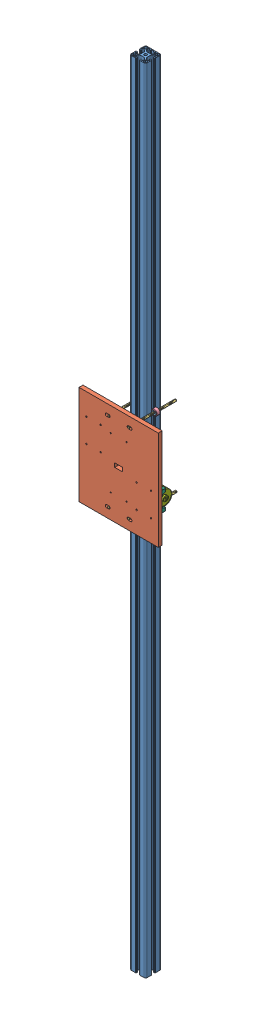
SolidWorks assembly assemblagecomplet, configuration Défaut. Lengths in mm.
Overall size (275.25 2000 121.11).
48 component instances, 14 part files, 17 mates.
Components (placement in the parent):
- rail-1: rail [Défaut] at (-24.0212 110.7646 2000) size (40 2000 40)
- suppport ameliore-1: suppport ameliore [Défaut] at (-123.9247 367.414 2058.0867) size (275.25 250 10)
- TigeFilet-1: TigeFilet [Défaut] at (-48.9247 342.414 2068.0867) x (1 0 0) z (0 1 0) size (5.15 120.44 5.77)
- TigeFilet-2: TigeFilet [Défaut] at (1.0753 342.414 2068.7589) x (-0.923728 -0.383049 0) z (0.383049 -0.923728 0) size (5.15 120.44 5.77)
- TigeFilet-3: TigeFilet [Défaut] at (1.0753 142.414 2068.0961) x (-0.923728 -0.383049 0) z (0.383049 -0.923728 0) size (5.15 120.44 5.77)
- TigeFilet-4: TigeFilet [Défaut] at (-48.9247 142.414 2068.4052) x (-0.728868 0.684654 0) z (-0.684654 -0.728868 0) size (5.15 120.44 5.77)
- RoueVAssemblage1-1: RoueVAssemblage1 [Défaut] at (-46.4189 341.2706 1984.8207) x (0.996447 0.084223 0) z (0 0 1) size (15.2 15.2 9)
  - RoueV1-1: RoueV1 [Défaut] at (-2.4006 1.3504 10.7) size (15.2 15.2 9)
  - RoueV2-1: RoueV2 [Défaut] at (-2.4006 1.3504 10.7) x (0.999854 -0.017094 0) z (0 0 1) size (10 10 9)
- SousAssemblageMoteurComplet-1: SousAssemblageMoteurComplet [Défaut] at (-133.3233 512.2521 1925.5591) x (1 0 0) z (0 -1 0) size (134.9 58.55 89.71)
  - MoteurEtSupport-1: MoteurEtSupport [Défaut] at (175.3767 115.3051 355.1381) x (0 1 0) z (0 0 -1) size (42.55 57.9 70)
    - SupportMoteur-1: SupportMoteur [Défaut] at (-2.7774 -21.4781 70) size (42.55 52 70)
    - Moteur-1: Moteur [Défaut] at (-4.7774 18.5219 45) x (1 0 0) z (0 -1 0) size (35.75 35.75 56.7)
  - piecemaintientchariot-1: piecemaintientchariot [Défaut] at (103.8575 100.6487 331.5754) size (50 31.79 18)
  - RoulementàBilles-1: RoulementàBilles [Défaut] at (106.8021 108.7409 335.5754) size (4 10 10)
  - Tige_entre_roues-1: Tige_entre_roues [Défaut] at (63.9986 108.7409 335.5754) size (80 3 3)
  - RoueAssemblee-1: RoueAssemblee [Défaut] at (119.9243 114.0834 363.6739) x (-1 0 0) z (0 -0.197919 -0.980218) size (16.9 28.6 28.6)
    - Roue1-1: Roue1 [Défaut] at (-7.3778 0.3244 28.6) size (13 28.6 28.6)
    - Roue2-1: Roue2 [Défaut] at (-7.6778 0.3244 28.6) x (0 -1 0) z (0 0 1) size (19 16.9 19)
  - RoueAssemblee-2: RoueAssemblee [Défaut] at (98.6799 108.2781 306.9773) x (1 0 0) z (0 0.004838 0.999988) size (16.9 28.6 28.6)
    - Roue1-1: Roue1 [Défaut] at (-7.3778 0.3244 28.6) size (13 28.6 28.6)
    - Roue2-1: Roue2 [Défaut] at (-7.6778 0.3244 28.6) x (0 -1 0) z (0 0 1) size (19 16.9 19)
  - PEngrenage-1: PEngrenage [Défaut] at (140.9986 110.5276 310.1381) x (1 0 0) z (0 0.064382 0.997925) size (7.5 9 9)
  - Gengrenage-1: Gengrenage [Défaut] at (143.9986 108.7409 335.5754) x (0 -0.815974 -0.578088) z (0 0.578088 -0.815974) size (42 8.4 42)
- SousAssemblageMoteurComplet-2: SousAssemblageMoteurComplet [Défaut] at (85.4739 -27.4241 1925.5591) x (-1 0 0) z (0 1 0) size (134.9 58.55 89.71)
  - MoteurEtSupport-1: MoteurEtSupport [Défaut] at (175.3767 115.3051 355.1381) x (0 1 0) z (0 0 -1) size (42.55 57.9 70)
    - SupportMoteur-1: SupportMoteur [Défaut] at (-2.7774 -21.4781 70) size (42.55 52 70)
    - Moteur-1: Moteur [Défaut] at (-4.7774 18.5219 45) x (1 0 0) z (0 -1 0) size (35.75 35.75 56.7)
  - piecemaintientchariot-1: piecemaintientchariot [Défaut] at (103.8575 100.6487 331.5754) size (50 31.79 18)
  - RoulementàBilles-1: RoulementàBilles [Défaut] at (106.8021 108.7409 335.5754) size (4 10 10)
  - Tige_entre_roues-1: Tige_entre_roues [Défaut] at (63.9986 108.7409 335.5754) size (80 3 3)
  - RoueAssemblee-1: RoueAssemblee [Défaut] at (119.9243 114.0834 363.6739) x (-1 0 0) z (0 -0.197919 -0.980218) size (16.9 28.6 28.6)
    - Roue1-1: Roue1 [Défaut] at (-7.3778 0.3244 28.6) size (13 28.6 28.6)
    - Roue2-1: Roue2 [Défaut] at (-7.6778 0.3244 28.6) x (0 -1 0) z (0 0 1) size (19 16.9 19)
  - RoueAssemblee-2: RoueAssemblee [Défaut] at (98.6799 108.2781 306.9773) x (1 0 0) z (0 0.004838 0.999988) size (16.9 28.6 28.6)
    - Roue1-1: Roue1 [Défaut] at (-7.3778 0.3244 28.6) size (13 28.6 28.6)
    - Roue2-1: Roue2 [Défaut] at (-7.6778 0.3244 28.6) x (0 -1 0) z (0 0 1) size (19 16.9 19)
  - PEngrenage-1: PEngrenage [Défaut] at (140.9986 110.5276 310.1381) x (1 0 0) z (0 0.064382 0.997925) size (7.5 9 9)
  - Gengrenage-1: Gengrenage [Défaut] at (143.9986 108.7409 335.5754) x (0 -0.815974 -0.578088) z (0 0.578088 -0.815974) size (42 8.4 42)
- RoueVAssemblage1-2: RoueVAssemblage1 [Défaut] at (-47.7266 144.8941 1984.6734) x (-0.062339 0.998055 0) z (0 0 1) size (15.2 15.2 9)
  - RoueV1-1: RoueV1 [Défaut] at (-2.4006 1.3504 10.7) size (15.2 15.2 9)
  - RoueV2-1: RoueV2 [Défaut] at (-2.4006 1.3504 10.7) x (0.999854 -0.017094 0) z (0 0 1) size (10 10 9)
- RoueVAssemblage1-3: RoueVAssemblage1 [Défaut] at (3.4744 341.0609 1984.6118) x (0.999999 -0.001144 0) z (0 0 1) size (15.2 15.2 9)
  - RoueV1-1: RoueV1 [Défaut] at (-2.4006 1.3504 10.7) size (15.2 15.2 9)
  - RoueV2-1: RoueV2 [Défaut] at (-2.4006 1.3504 10.7) x (0.999854 -0.017094 0) z (0 0 1) size (10 10 9)
- RoueVAssemblage1-4: RoueVAssemblage1 [Défaut] at (3.7583 141.7909 1984.8978) x (0.959883 0.2804 0) z (0 0 1) size (15.2 15.2 9)
  - RoueV1-1: RoueV1 [Défaut] at (-2.4006 1.3504 10.7) size (15.2 15.2 9)
  - RoueV2-1: RoueV2 [Défaut] at (-2.4006 1.3504 10.7) x (0.999854 -0.017094 0) z (0 0 1) size (10 10 9)
Mates (geometry in assembly coordinates):
- Coaxiale29: concentric: circle of TigeFilet-1; circle of RoueVAssemblage1-1/RoueV2-1
- Coaxiale31: concentric: cylinder of suppport ameliore-1 through (57.5753 172.114 2068.0867) axis (0 0 1) radius 1.7; circle of SousAssemblageMoteurComplet-1/MoteurEtSupport-1/SupportMoteur-1
- Coïncidente3: coincident: plane of suppport ameliore-1 through (-123.9247 367.414 2058.0867) normal (0 0 -1); plane of SousAssemblageMoteurComplet-1/MoteurEtSupport-1/SupportMoteur-1 through (65.5753 227.114 2058.0867) normal (0 0 1)
- Coaxiale40: concentric: circle of suppport ameliore-1; circle of SousAssemblageMoteurComplet-2/MoteurEtSupport-1/SupportMoteur-1
- Coaxiale41: concentric: circle of suppport ameliore-1; cylinder of SousAssemblageMoteurComplet-2/MoteurEtSupport-1/SupportMoteur-1 through (-105.4247 312.714 2063.0867) axis (0 0 -1) radius 1.2295
- Coïncidente5: coincident: plane of suppport ameliore-1 through (-123.9247 367.414 2058.0867) normal (0 0 -1); plane of SousAssemblageMoteurComplet-2/MoteurEtSupport-1/SupportMoteur-1 through (-113.4247 257.714 2058.0867) normal (0 0 1)
- Tangent4: tangent: plane of rail-1 through (-24.0212 1110.7646 2020) normal (0 0 1); cylinder of SousAssemblageMoteurComplet-1/RoueAssemblee-2/Roue1-1 through (-53.3626 176.6767 2034.3) axis (-1 0 0) radius 14.3
- Distance1: distance = 17.5 mm: plane of rail-1 through (-44.0212 1110.7646 2000) normal (-1 0 0); plane of SousAssemblageMoteurComplet-1/piecemaintientchariot-1 through (-26.5212 172.6767 2040.3) normal (-1 0 0)
- Parallèle19: parallel: plane of rail-1 through (-44.0212 1110.7646 2000) normal (-1 0 0); plane of suppport ameliore-1 through (-123.9247 367.414 2068.0867) normal (-1 0 0)
- Coaxiale44: concentric: circle of suppport ameliore-1; circle of TigeFilet-1
- Perpendiculaire2: perpendicular: plane of rail-1 through (-24.0212 1110.7646 2020) normal (0 0 1); plane of suppport ameliore-1 through (-123.9247 367.414 2068.0867) normal (0 1 0)
- Coaxiale45: concentric: circle of suppport ameliore-1; circle of TigeFilet-2
- Coaxiale46: concentric: circle of suppport ameliore-1; circle of TigeFilet-4
- Coaxiale47: concentric: circle of suppport ameliore-1; circle of TigeFilet-3
- Coaxiale48: concentric: circle of TigeFilet-4; circle of RoueVAssemblage1-2/RoueV2-1
- Coaxiale52: concentric: circle of TigeFilet-2; circle of RoueVAssemblage1-3/RoueV2-1
- Coaxiale53: concentric: circle of TigeFilet-3; circle of RoueVAssemblage1-4/RoueV2-1
